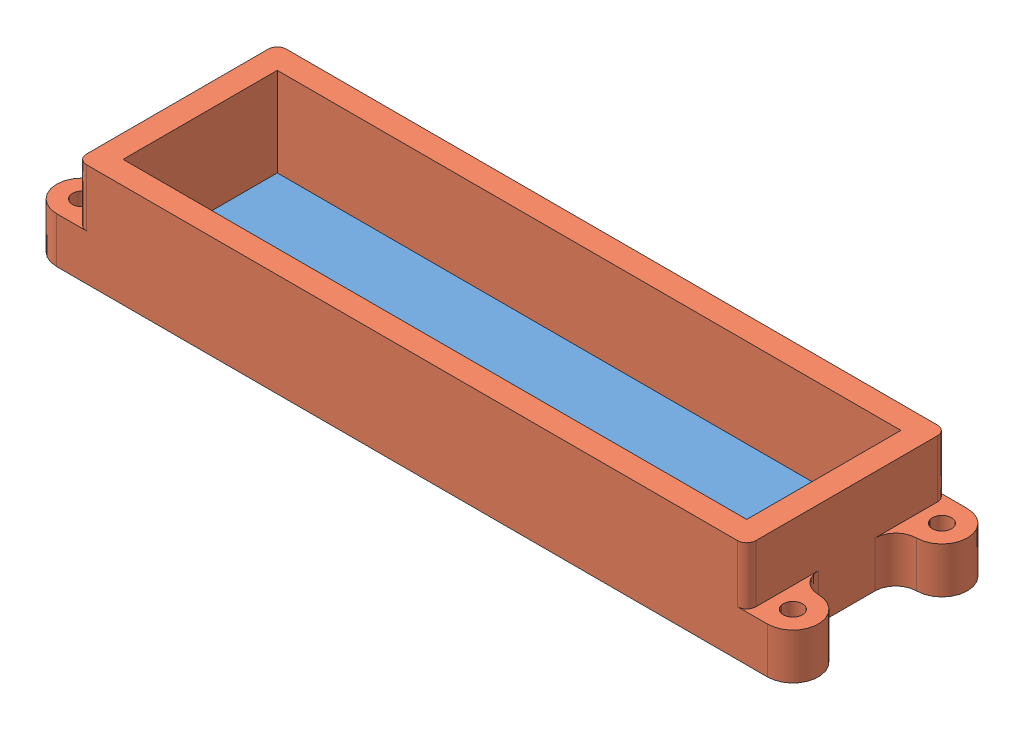
SolidWorks assembly voltage multplyer circut and housingSLDASM, configuration Default. Lengths in mm.
Overall size (210.97 28.57 55.4).
4 component instances, 3 part files, 7 mates.
Components (placement in the parent):
- voltage-multiplyer PCB-1: voltage-multiplyer PCB [Default] at (-104.5173 11.385 19.9309) size (160 0.8 30)
- voltage-multiplyer vat-1: voltage-multiplyer vat [Default] at (-117.2173 1.86 32.6309) size (210.97 28.57 55.4)
- B18.3.1M - 2 x 0.4 x 4 Hex SHCS -- 4NHX-1: B18.3.1M - 2 x 0.4 x 4 Hex SHCS -- 4NHX [B18.3.1M - 2 x 0.4 x 4 Hex SHCS -- 4NHX] at (25.4827 14.185 11.9309) x (0 -1 0) z (0 0 1) size (6 3.8 3.8)
- B18.3.1M - 2 x 0.4 x 4 Hex SHCS -- 4NHX-2: B18.3.1M - 2 x 0.4 x 4 Hex SHCS -- 4NHX [B18.3.1M - 2 x 0.4 x 4 Hex SHCS -- 4NHX] at (-74.5173 14.185 11.9309) x (0 -1 0) z (0 0 1) size (6 3.8 3.8)
Mates (geometry in assembly coordinates):
- Concentric1: concentric anti-aligned: cylinder of voltage-multiplyer PCB-1 through (-74.5173 12.185 11.9309) axis (0 -1 0) radius 1.1; cylinder of voltage-multiplyer vat-1 through (-74.5173 11.385 11.9309) axis (0 1 0) radius 0.8
- Coincident1: coincident anti-aligned: plane of voltage-multiplyer PCB-1 through (-104.5173 11.385 19.9309) normal (0 -1 0); plane of voltage-multiplyer vat-1 through (-74.5173 11.385 11.9309) normal (0 1 0)
- Concentric2: concentric anti-aligned: cylinder of voltage-multiplyer PCB-1 through (25.4827 12.185 11.9309) axis (0 -1 0) radius 1.1; cylinder of voltage-multiplyer vat-1 through (25.4827 11.385 11.9309) axis (0 1 0) radius 0.8
- Concentric3: concentric anti-aligned: cylinder of voltage-multiplyer PCB-1 through (25.4827 12.185 11.9309) axis (0 -1 0) radius 1.1; cylinder of B18.3.1M - 2 x 0.4 x 4 Hex SHCS -- 4NHX-1 through (25.4827 45.935 11.9309) axis (0 1 0) radius 1.9
- Coincident2: coincident anti-aligned: plane of voltage-multiplyer PCB-1 through (-104.5173 12.185 19.9309) normal (0 1 0); plane of B18.3.1M - 2 x 0.4 x 4 Hex SHCS -- 4NHX-1 through (27.3827 12.185 11.9309) normal (0 -1 0)
- Concentric41: concentric anti-aligned: cylinder of voltage-multiplyer PCB-1 through (-74.5173 12.185 11.9309) axis (0 -1 0) radius 1.1; cylinder of B18.3.1M - 2 x 0.4 x 4 Hex SHCS -- 4NHX-2 through (-74.5173 45.935 11.9309) axis (0 1 0) radius 1.9
- Coincident31: coincident anti-aligned: plane of voltage-multiplyer PCB-1 through (-104.5173 12.185 19.9309) normal (0 1 0); plane of B18.3.1M - 2 x 0.4 x 4 Hex SHCS -- 4NHX-2 through (-72.6173 12.185 11.9309) normal (0 -1 0)
